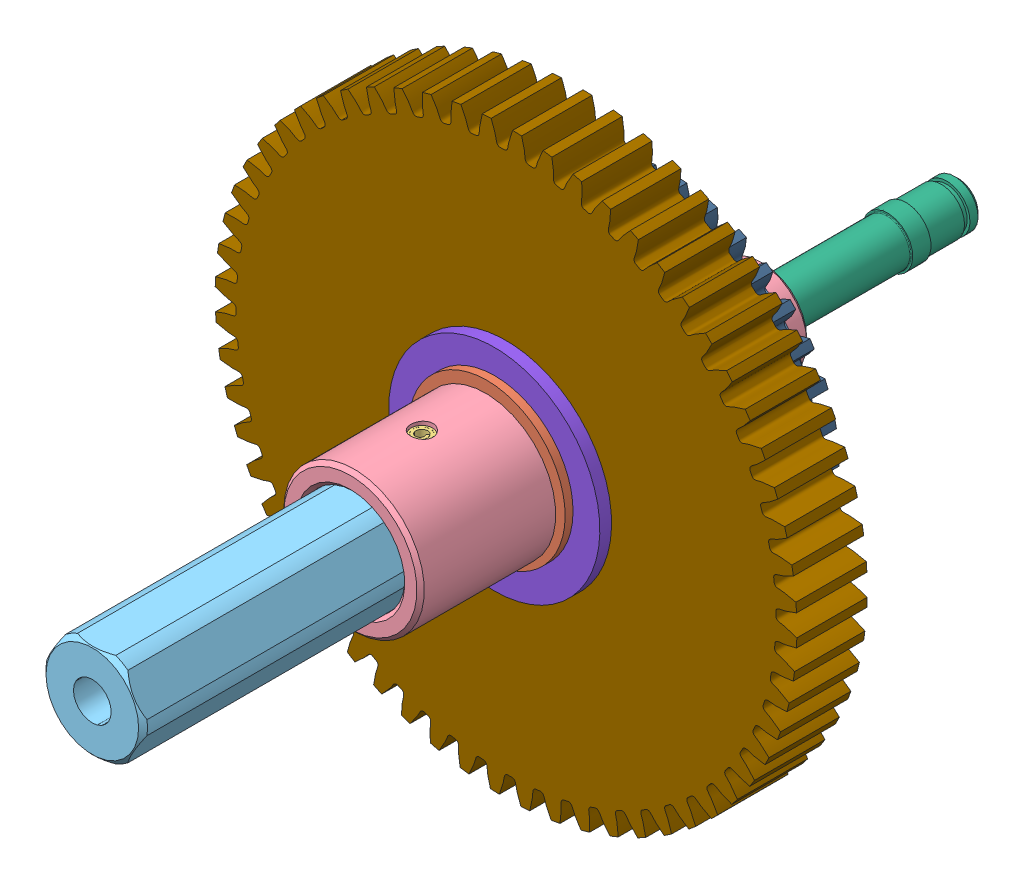
SolidWorks assembly 217-3292-STEP-20150102, configuration Default. Lengths in mm.
Overall size (107.38 107.38 117.22).
19 component instances, 10 part files, 0 mates.
Components (placement in the parent):
- 217-2428-008 Rev2-1: 217-2428-008 Rev2 [Default] at (0 0 10.2679) size (31.75 31.75 1.59)
- 217-2428-028 Rev1_97633A250-1: 217-2428-028 Rev1_97633A250 [Default] at (0 0 37.1221) x (0 0 1) z (0.9357 -0.352797 0) size (1.07 23.39 21.18)
- 217-4098-000 Rev2-1: 217-4098-000 Rev2 [Default] x (-1 0 0) z (0 0 1) size (22.23 22.23 117.22)
  - 217-4098-005 Rev1_91612A226-1: 217-4098-005 Rev1_91612A226 [Default] at (0 0 46.2661) x (-0.144757 0 0.989467) z (0 -1 0) size (3.02 3.15 18.22)
  - 217-4098-003 Rev2-1: 217-4098-003 Rev2 [Default] x (1 0 0) z (0 0 -1) size (22.23 22.23 55.94)
  - 217-4098-002 Rev3-1: 217-4098-002 Rev3 [Default] at (0 0 62.9285) x (0 0 1) z (-1 0 0) size (59.88 12.73 14.67)
  - 217-4098-004 Rev1-1: 217-4098-004 Rev1 [Default] at (0 0 14.2494) x (0.946095 -0.32389 0) z (0 0 1) size (11.68 11.68 56)
- 217-2428-007 Rev1-1: 217-2428-007 Rev1 [Default] at (7.809 4.5085 14.2494) x (-0.595009 -0.090706 -0.798584) z (-0.272616 -0.911929 0.306701) size (6.35 6.35 6.35)
- 217-2428-007 Rev1-2: 217-2428-007 Rev1 [Default] at (5.4343 3.1375 26.9494) x (0.72734 0.013635 -0.686142) z (-0.675044 -0.165943 -0.718874) size (6.35 6.35 6.35)
- 217-2713-101 Rev1-1: 217-2713-101 Rev1 [Default] at (0 0 30.1117) x (0.872992 -0.487734 0) z (0 0 -1) size (78.91 78.91 12.7)
  - 217-2428-022 Rev1-1: 217-2428-022 Rev1 [Default] at (0 0 -3.302) size (28.57 28.57 6.1)
  - 217-2713-001_60t Steel-1: 217-2713-001_60t Steel [Default] at origin size (78.91 78.91 11.11)
- 217-3212-101 Rev1-1: 217-3212-101 Rev1 [Default] at (-10.5029 11.4936 45.3224) x (0.956719 0.291014 0) z (0 0 -1) size (46.46 46.56 12.7)
  - 217-2428-022 Rev1-1: 217-2428-022 Rev1 [Default] at (6.7035 14.0527 24.6087) size (28.57 28.57 6.1)
  - 217-3212-001 Rev1_34t-1: 217-3212-001 Rev1_34t [Default] at (6.7035 14.0527 27.9107) size (46.46 46.56 11.11)
- 217-2428-007 Rev1-3: 217-2428-007 Rev1 [Default] at (-0.1535 -8.084 14.2494) x (0.218951 0.560646 -0.798584) z (-0.653446 0.692057 0.306701) size (6.35 6.35 6.35)
- 217-2428-007 Rev1-4: 217-2428-007 Rev1 [Default] at (-7.0777 5.1079 14.2494) x (0.376058 -0.46994 -0.798584) z (0.926062 0.219872 0.306701) size (6.35 6.35 6.35)
- 217-2428-007 Rev1-5: 217-2428-007 Rev1 [Default] at (-0.1535 -5.342 26.9494) x (-0.351862 -0.636713 -0.686142) z (0.193811 0.667576 -0.718874) size (6.35 6.35 6.35)
- 217-2428-007 Rev1-6: 217-2428-007 Rev1 [Default] at (-4.703 3.7369 26.9494) x (-0.375478 0.623078 -0.686142) z (0.481232 -0.501634 -0.718874) size (6.35 6.35 6.35)
